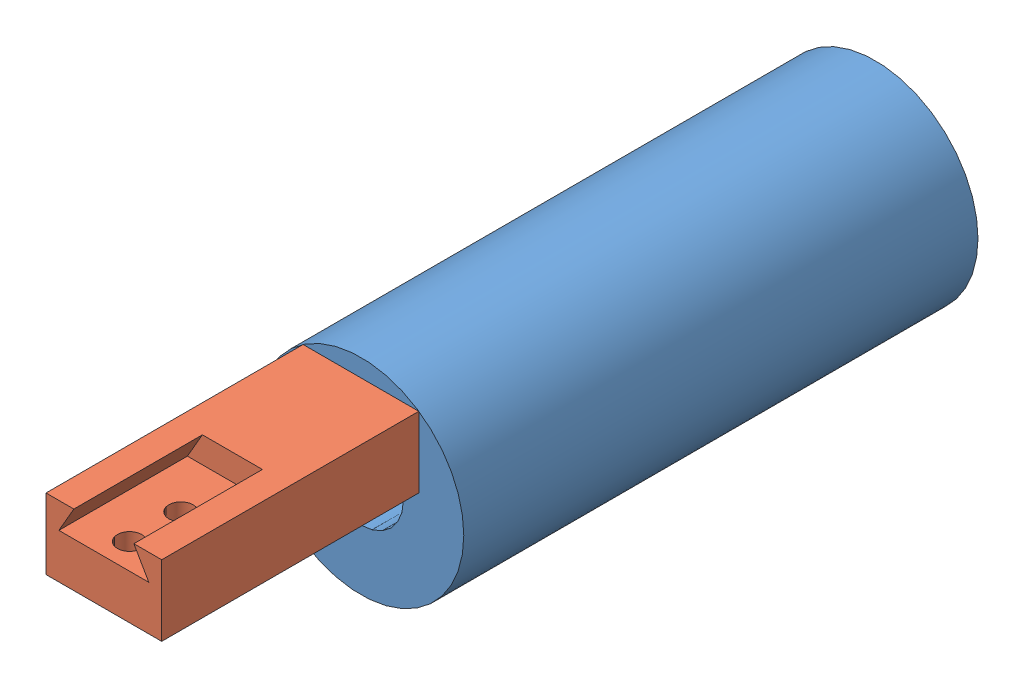
SolidWorks assembly rod_with_slider_holder_3mm5, configuration Default. Lengths in mm.
Overall size (8 9.33 30).
2 component instances, 2 part files, 6 mates.
Components (placement in the parent):
- rod_stereotax_m4-1: rod_stereotax_m4 [Default] at (-18.071 14.8811 -20.5742) size (8 8 20)
- slider_3mm5-1: slider_3mm5 [female] at (-18.071 18.1883 4.4258) x (0 0 1) z (-1 0 0) size (10 4.77 4.5)
Mates (geometry in assembly coordinates):
- Coincident1: coincident aligned: plane of rod_stereotax_m4-1 through (-18.071 14.8811 -20.5742) normal (1 0 0); plane of slider-1 through (-18.071 17.8853 24.4258) normal (1 0 0)
- Coincident2: coincident anti-aligned: plane of rod_stereotax_m4-1 through (-18.071 14.8811 -0.5742) normal (0 0 1); plane of slider-1 through (-18.071 17.8853 9.4258) normal (0 0 -1)
- Tangent2: tangent anti-aligned: cylinder of rod_stereotax_m4-1 through (-18.071 14.8811 -20.5742) axis (0 0 -1) radius 1.65; plane of slider-1 through (-18.071 16.5311 29.4258) normal (0 -1 0)
- Coincident3: coincident anti-aligned: plane of rod_stereotax_m4-1 through (-18.071 14.8811 -0.5742) normal (0 0 1); plane of slider_3mm5-1 through (-18.071 18.1883 -0.5742) normal (0 0 -1)
- Coincident4: coincident anti-aligned: plane of slider_3mm5-1 through (-18.071 18.1883 4.4258) normal (-1 0 0); plane of rod_stereotax_m4-1 through (-18.071 14.8811 -20.5742) normal (1 0 0)
- Coincident5: coincident: circle of rod_stereotax_m4-1; point of slider_3mm5-1
